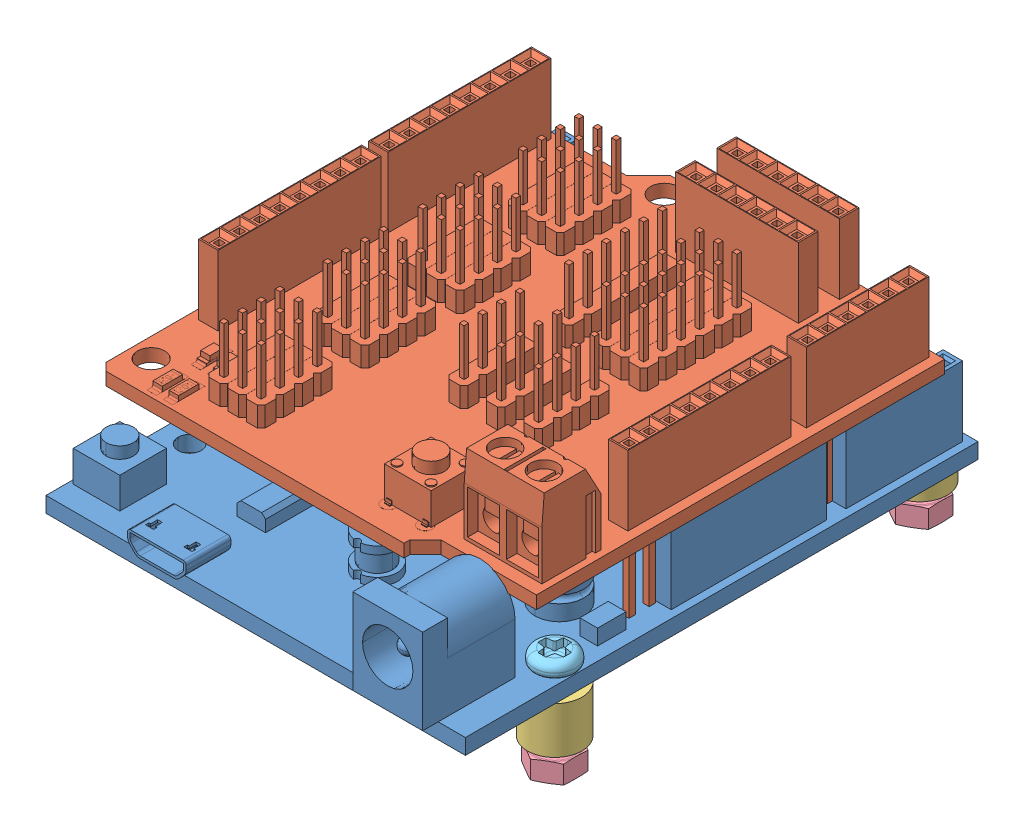
SolidWorks assembly WE, configuration Predeterminado. Lengths in mm.
Overall size (55.33 32.24 72.84).
11 component instances, 5 part files, 21 mates.
Components (placement in the parent):
- wemosd1r32-1: wemosd1r32 [Predeterminado] at (-5.5887 -7.5717 70.5) size (54 14.5 70.5)
- Arduino Sensor Board V1-1: Arduino Sensor Board V1 [Predeterminado] at (-6.0937 1.4283 68.61) size (53.65 20.91 58.16)
- separador-1: separador [Predeterminado] at (18.9113 -9.5717 90.75) x (1 0 0) z (0 -1 0) size (7 7 6)
- M3 Nut-1: M3 Nut [Predeterminado] at (18.9113 -20.5717 90.75) x (1 0 0) z (0 -1 0) size (6.27 6.27 2.71)
- M3x10 Philips Screw-1: M3x10 Philips Screw [Predeterminado] at (18.9113 -7.5717 90.75) x (1 0 0) z (0 1 0) size (5.3 5.3 11.8)
- M3x10 Philips Screw-2: M3x10 Philips Screw [Predeterminado] at (13.9113 -7.5717 38.75) x (1 0 0) z (0 1 0) size (5.3 5.3 11.8)
- separador-2: separador [Predeterminado] at (13.9113 -9.5717 38.75) x (-0.837169 0 -0.546944) z (0 -1 0) size (7 7 6)
- M3 Nut-2: M3 Nut [Predeterminado] at (13.9113 -20.5717 38.75) x (1 0 0) z (0 -1 0) size (6.27 6.27 2.71)
- M3x10 Philips Screw-3: M3x10 Philips Screw [Predeterminado] at (-14.0887 -7.5717 38.75) x (1 0 0) z (0 1 0) size (5.3 5.3 11.8)
- M3 Nut-3: M3 Nut [Predeterminado] at (-14.0887 -20.5717 38.75) x (1 0 0) z (0 -1 0) size (6.27 6.27 2.71)
- separador-3: separador [Predeterminado] at (-14.0887 -9.5717 38.75) x (1 0 0) z (0 -1 0) size (7 7 6)
Mates (geometry in assembly coordinates):
- Coincidente1: coincident: plane of wemosd1r32-1 through (-30.8387 -7.5717 85) normal (1 0 0); plane of Arduino Sensor Board V1-1 through (-30.8387 1.4283 85) normal (-1 0 0)
- Coincidente2: coincident: plane of wemosd1r32-1 through (-29.8387 -7.5717 85) normal (0 0 -1); plane of Arduino Sensor Board V1-1 through (-30.0387 1.4283 85) normal (0 0 1)
- Coincidente3: coincident: plane of wemosd1r32-1 through (-5.5887 1.4283 70.5) normal (0 1 0); plane of Arduino Sensor Board V1-1 through (-6.0893 1.4283 68.9855) normal (0 -1 0)
- Coincidente4: coincident: plane of wemosd1r32-1 through (-5.5887 -7.5717 70.5) normal (0 1 0); plane of M3x10 Philips Screw-1 through (18.9113 -7.5717 89.15) normal (0 -1 0)
- Concéntrica1: concentric: circle of wemosd1r32-1; circle of M3x10 Philips Screw-1
- Coincidente5: coincident: plane of wemosd1r32-1 through (-5.5887 -9.5717 70.5) normal (0 -1 0); plane of separador-1 through (18.9113 -9.5717 90.75) normal (0 1 0)
- Concéntrica2: concentric: circle of wemosd1r32-1; circle of separador-1
- Distancia1: distance = 1 mm: plane of M3 Nut-1 through (18.9113 -16.5717 90.75) normal (0 1 0); plane of separador-1 through (18.9113 -15.5717 90.75) normal (0 -1 0)
- Concéntrica3: concentric: circle of separador-1; circle of M3 Nut-1
- Coincidente7: coincident: plane of wemosd1r32-1 through (-5.5887 -7.5717 70.5) normal (0 1 0); plane of M3x10 Philips Screw-2 through (13.9113 -7.5717 37.15) normal (0 -1 0)
- Concéntrica4: concentric: circle of wemosd1r32-1; circle of M3x10 Philips Screw-2
- Coincidente8: coincident: plane of wemosd1r32-1 through (-5.5887 -9.5717 70.5) normal (0 -1 0); circle of separador-2
- Concéntrica5: concentric: circle of wemosd1r32-1; circle of separador-2
- Distancia2: distance = 1 mm: plane of M3 Nut-2 through (13.9113 -16.5717 38.75) normal (0 1 0); plane of separador-2 through (13.9113 -15.5717 38.75) normal (0 -1 0)
- Concéntrica6: concentric: circle of separador-2; circle of M3 Nut-2
- Coincidente10: coincident: plane of wemosd1r32-1 through (-5.5887 -7.5717 70.5) normal (0 1 0); plane of M3x10 Philips Screw-3 through (-14.0887 -7.5717 37.15) normal (0 -1 0)
- Concéntrica7: concentric: circle of wemosd1r32-1; circle of M3x10 Philips Screw-3
- Coincidente11: coincident: plane of wemosd1r32-1 through (-5.5887 -9.5717 70.5) normal (0 -1 0); plane of separador-3 through (-14.0887 -9.5717 38.75) normal (0 1 0)
- Concéntrica8: concentric: circle of wemosd1r32-1; circle of separador-3
- Concéntrica9: concentric: circle of M3 Nut-3; circle of separador-3
- Distancia3: distance = 1 mm: plane of M3 Nut-3 through (-14.0887 -16.5717 38.75) normal (0 1 0); plane of separador-3 through (-14.0887 -15.5717 38.75) normal (0 -1 0)
